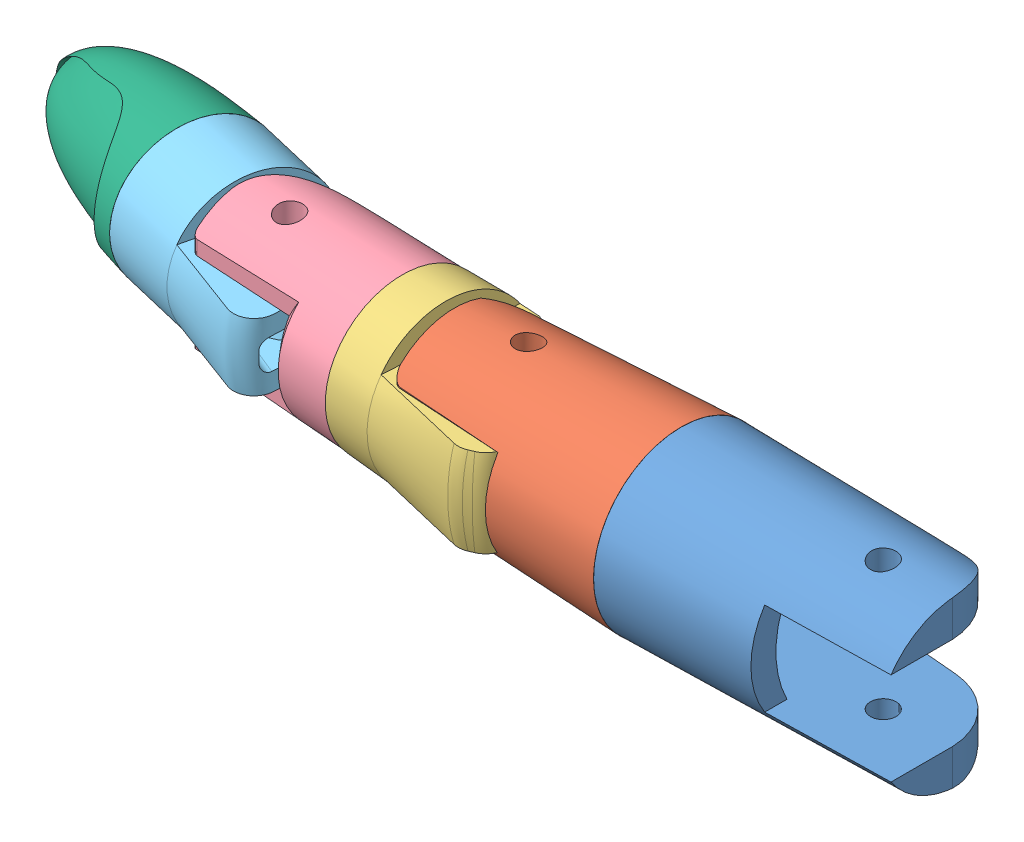
SolidWorks assembly articulatie3 montaj, configuration Default. Lengths in mm.
Overall size (80.07 14.17 19.79).
6 component instances, 6 part files, 18 mates.
Components (placement in the parent):
- articulatie3-4-1: articulatie3-4 [Default] x (0 -1 0) z (0 0 1) size (14.17 22.51 14.17)
- articulatie3-3-1: articulatie3-3 [Default] at origin size (18.34 14.17 14.17)
- articulatie3-5-1: articulatie3-5 [Default] at (-22.7616 0 -0.5946) x (0.998236 0 0.05937) z (0 -1 0) size (14.57 13.77 12.85)
- articulatie3-6-1: articulatie3-6 [Default] at (-36.0741 0 -1.3863) x (0.998236 0 0.05937) z (0.05937 0 -0.998236) size (13.34 12.77 12.44)
- articulatie3-2-2: articulatie3-2 [Default] at (-42.4072 0 -3.224) x (-0.23181 0 0.972761) z (0.972761 0 0.23181) size (12.3 11.75 15.1)
- articulatie3-1: articulatie3 [Default] at (-42.408 0 -3.2207) x (0 1 0) z (-0.23181 0 0.972761) size (11.69 14.19 11.69)
Mates (geometry in assembly coordinates):
- Coincident2: coincident aligned: plane of articulatie3-4-1 through (0 0 0) normal (0 0 1)
- Coincident4: coincident anti-aligned: plane of articulatie3-4-1 through (0 0 0) normal (0 -1 0)
- Coincident6: coincident aligned: plane of articulatie3-4-1 through (0 0 0) normal (1 0 0)
- Concentric1: concentric anti-aligned: cone of articulatie3-4-1 through (0 0 0) axis (1 0 0); cone of articulatie3-3-1 through (-18.337 0 0) axis (-1 0 0)
- Coincident7: coincident anti-aligned: plane of articulatie3-4-1 through (0 0 0) normal (-1 0 0); plane of articulatie3-3-1 through (0 0 0) normal (1 0 0)
- Coincident8: coincident aligned: plane of articulatie3-4-1 through (0 0 0) normal (0 0 1); plane of articulatie3-3-1 through (0 0 0) normal (0 0 1)
- Concentric3: concentric aligned: cylinder of articulatie3-3-1 through (-12.7525 8.335 -0.4168) axis (0 -1 0) radius 1.0419; cylinder of articulatie3-5-1 through (-12.7525 6.4239 -0.4168) axis (0 -1 0) radius 1.0419
- Coincident10: coincident anti-aligned: plane of articulatie3-3-1 through (-20.8208 3.5424 8.335) normal (0 -1 0); plane of articulatie3-5-1 through (-14.2576 3.5424 0.9108) normal (0 1 0)
- LimitAngle2: limit planar angle = 3.082188 rad anti-aligned: plane of articulatie3-5-1 through (-22.7616 0 -0.5946) normal (-0.05937 0 0.998236); plane of articulatie3-3-1 through (0 0 0) normal (0 0 1)
- Concentric4: concentric aligned: cone of articulatie3-5-1 through (-22.7616 0 -0.5946) axis (-0.998236 0 -0.05937); cone of articulatie3-6-1 through (-21.0976 0 -0.4956) axis (-0.998236 0 -0.05937)
- Coincident12: coincident anti-aligned: plane of articulatie3-5-1 through (-22.7616 0 -0.5946) normal (-0.998236 0 -0.05937); plane of articulatie3-6-1 through (-23.1328 19.3789 5.6457) normal (0.998236 0 0.05937)
- Coincident13: coincident anti-aligned: plane of articulatie3-5-1 through (-22.7616 0 -0.5946) normal (-0.05937 0 0.998236); plane of articulatie3-6-1 through (-36.0741 0 -1.3863) normal (0.05937 0 -0.998236)
- Concentric5: concentric aligned: cylinder of articulatie3-6-1 through (-31.9635 6.2512 -0.3069) axis (0 -1 0) radius 1.0419; cylinder of articulatie3-2-2 through (-31.9635 5.8762 -0.3069) axis (0 -1 0) radius 1.0419
- Width1: width anti-aligned: plane of articulatie3-2-2 through (-30.4193 -2.7089 4.1213) normal (0 -1 0); plane of articulatie3-2-2 through (-30.4185 2.7089 4.1182) normal (0 1 0); plane of articulatie3-6-1 through (-36.0741 2.7089 -1.3863) normal (0 -1 0); plane of articulatie3-6-1 through (-36.0741 -2.7089 -1.3863) normal (0 1 0)
- LimitAngle4: limit planar angle = 2.96706 rad aligned: plane of articulatie3-2-2 through (-42.4072 0 -3.224) normal (-0.23181 0 0.972761); plane of articulatie3-6-1 through (-36.0741 0 -1.3863) normal (0.05937 0 -0.998236)
- Concentric6: concentric anti-aligned: circle of articulatie3-2-2; circle of articulatie3-1
- Coincident17: coincident anti-aligned: plane of articulatie3-2-2 through (-42.4072 0 -3.224) normal (-0.972761 0 -0.23181); circle of articulatie3-1
- Parallel4: parallel aligned: plane of articulatie3-2-2 through (-42.4072 0 -3.224) normal (-0.23181 0 0.972761); plane of articulatie3-1 through (-42.408 0 -3.2207) normal (-0.23181 0 0.972761)
